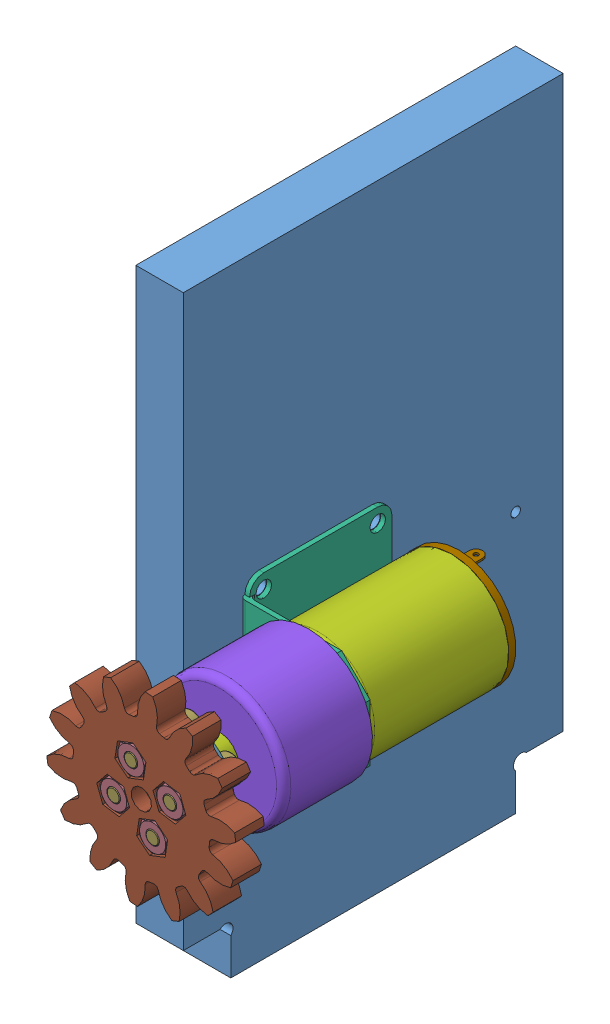
SolidWorks assembly moteur-complet, configuration Défaut. Lengths in mm.
Overall size (63.55 130 103.25).
26 component instances, 15 part files, 14 mates.
Components (placement in the parent):
- moteur-platine-1: moteur-platine [Défaut] at (-59.9962 -68.9698 170) size (10 130 80)
- Grove button-1: Grove button [Défaut] at (-60.7015 -11.8903 110) x (0 -1 0) z (0 0 -1) size (20 11.6 23.6)
  - PCB grove 20x20-1: PCB grove 20x20 [Défaut] at (2.0795 1.2947 0) size (20 1.6 23.6)
  - 603 resistor 102-1: 603 resistor 102 [Default] at (2.0895 2.8947 -6.319) x (0 0 1) z (-1 0 0) size (2.36 0.62 1.03)
  - tactileswitch-CMS-1: tactileswitch-CMS [Default] at (-2.4169 2.8947 0.0035) x (0 0 1) z (-1 0 0) size (8.41 4.95 6.01)
  - Connecteur Grove (droit CMS)-1: Connecteur Grove (droit CMS) [Défaut] at (5.0795 2.8947 0) x (-1 0 0) z (0 1 0) size (6.5 14 10)
  - 603 resistor 102-2: 603 resistor 102 [Default] at (3.5895 2.8947 -6.319) x (0 0 1) z (-1 0 0) size (2.36 0.62 1.03)
- moteur MFA-1: moteur MFA [Défaut] at (-37.4916 -12.5198 142.6632) x (0 0 -1) z (0 -1 0) size (69.13 27.9 30)
  - moteur-support-1: moteur-support [Défaut] at (-14.3868 -12.5047 0) size (31 26.4 30)
  - moteur-corps-1: moteur-corps [Défaut] at (14.8132 1.8953 0) x (0 0 1) z (-1 0 0) size (24 24 62.63)
  - moteur-capuchon-1: moteur-capuchon [Défaut] at (-15.3868 1.8953 0) x (0 0 1) z (-1 0 0) size (27 27 18.7)
  - moteur-arriere-1: moteur-arriere [Défaut] at (16.3132 1.8953 0) x (0 0 1) z (-1 0 0) size (24 24 6.5)
- entretoise-grove-6: entretoise-grove [Défaut] at (-61.9962 -13.9698 120) x (0 0 -1) z (1 0 0) size (4 4 2)
- entretoise-grove-7: entretoise-grove [Défaut] at (-61.9962 -13.9698 100) x (0 0 -1) z (1 0 0) size (4 4 2)
- engrenage-complet-1: engrenage-complet [Défaut] at (-35.1676 -12.7474 193.25) x (0.932852 0.36026 0) z (0 0 -1) size (39.32 40 13)
  - engrenage-1: engrenage [Défaut] at (1.0609 0.1936 0) size (39.32 40 6)
  - vis-chc-2: vis-chc [Vis CHC M3x10] at (6.0322 -0.3667 10) x (0.997256 0.074024 0) z (0.074024 -0.997256 0) size (5.5 13 5.5)
  - ecrou-h-1: ecrou-h [6012 HU M3] at (6.0322 -0.3667 0.1) x (1 0 0) z (0 1 0) size (5.5 2.4 6.35)
  - engrenage-moyeu-1: engrenage-moyeu [Défaut] at (-0.3178 -0.3667 7.5) x (0.707107 -0.707107 0) z (0 0 1) size (19 19 5)
  - vis-chc-3: vis-chc [Vis CHC M3x10] at (-0.3178 5.9833 10) x (0.997256 0.074024 0) z (0.074024 -0.997256 0) size (5.5 13 5.5)
  - vis-chc-4: vis-chc [Vis CHC M3x10] at (-6.6678 -0.3667 10) x (0.997256 0.074024 0) z (0.074024 -0.997256 0) size (5.5 13 5.5)
  - vis-chc-5: vis-chc [Vis CHC M3x10] at (-0.3178 -6.7167 10) x (0.997256 0.074024 0) z (0.074024 -0.997256 0) size (5.5 13 5.5)
  - ecrou-h-2: ecrou-h [6012 HU M3] at (-6.6678 -0.3667 0.1) x (0.5 0.866025 0) z (-0.866025 0.5 0) size (5.5 2.4 6.35)
  - ecrou-h-3: ecrou-h [6012 HU M3] at (-0.3178 5.9833 0.1) x (0.866025 0.5 0) z (-0.5 0.866025 0) size (5.5 2.4 6.35)
  - ecrou-h-4: ecrou-h [6012 HU M3] at (-0.3178 -6.7167 0.1) x (0.866025 0.5 0) z (-0.5 0.866025 0) size (5.5 2.4 6.35)
- vis-sthc-m3x5-1: vis-sthc-m3x5 [Défaut] at (-38.4304 -18.9204 185.75) x (0.517554 -0.229174 -0.824389) z (-0.404884 -0.914368 0) size (3.08 3.15 5.22)
Mates (geometry in assembly coordinates):
- Coïncidente1: coincident anti-aligned: plane of moteur-platine-1 through (-49.9962 -60.1012 161.1314) normal (1 0 0); plane of moteur MFA 12-24V-1/Support moteur-1 through (-49.9962 -24.5198 154.05) normal (-1 0 0)
- Coaxiale1: concentric anti-aligned: cylinder of moteur-platine-1 through (-59.9962 -0.5198 130.05) axis (1 0 0) radius 1.5; cylinder of moteur MFA 12-24V-1/Support moteur-1 through (-23.5962 -0.5198 130.05) axis (-1 0 0) radius 1.65
- Coaxiale2: concentric anti-aligned: cylinder of moteur-platine-1 through (-59.9962 -24.5198 130.05) axis (1 0 0) radius 1.5; cylinder of moteur MFA 12-24V-1/Support moteur-1 through (-23.5962 -24.5198 130.05) axis (-1 0 0) radius 1.65
- Coaxiale9: concentric anti-aligned: cylinder of Grove button-1/PCB grove 20x20-1 through (-63.5962 -13.9698 120) axis (1 0 0) radius 1.1; cylinder of entretoise-grove-6 through (-59.9962 -13.9698 120) axis (-1 0 0) radius 1.2
- Coaxiale10: concentric anti-aligned: cylinder of Grove button-1/PCB grove 20x20-1 through (-63.5962 -13.9698 100) axis (1 0 0) radius 1.1; cylinder of entretoise-grove-7 through (-59.9962 -13.9698 100) axis (-1 0 0) radius 1.2
- Coïncidente11: coincident anti-aligned: plane of Grove button-1/PCB grove 20x20-1 through (-61.9962 -13.9698 110) normal (1 0 0); plane of entretoise-grove-7 through (-61.9962 -13.9698 100) normal (-1 0 0)
- Coïncidente12: coincident anti-aligned: plane of Grove button-1/PCB grove 20x20-1 through (-61.9962 -13.9698 110) normal (1 0 0); plane of entretoise-grove-6 through (-61.9962 -13.9698 120) normal (-1 0 0)
- Coïncidente13: coincident anti-aligned: plane of moteur-platine-1 through (-59.9962 -60.1012 161.1314) normal (-1 0 0); plane of entretoise-grove-7 through (-59.9962 -13.9698 100) normal (1 0 0)
- Coaxiale11: concentric anti-aligned: cylinder of moteur-platine-1 through (-59.9962 -13.9698 100) axis (1 0 0) radius 1; cylinder of entretoise-grove-7 through (-59.9962 -13.9698 100) axis (-1 0 0) radius 1.2
- Coaxiale12: concentric anti-aligned: cylinder of moteur-platine-1 through (-59.9962 -13.9698 120) axis (1 0 0) radius 1; cylinder of entretoise-grove-6 through (-59.9962 -13.9698 120) axis (-1 0 0) radius 1.2
- Distance2: distance = 10.5 mm anti-aligned: plane of engrenage-complet-1/engrenage-1 through (-35.5962 -12.5198 187.25) normal (0 0 -1); plane of moteur MFA-1/moteur-capuchon-1 through (-35.5962 -12.5198 176.75) normal (0 0 1)
- Coaxiale13: concentric aligned: cylinder of engrenage-complet-1/engrenage-moyeu-1 through (-42.0744 -27.1497 185.75) axis (0.404884 0.914368 0) radius 1.5; cone of vis-sthc-m3x5-1 through (-36.5072 -14.5771 185.75) axis (0.404884 0.914368 0)
- Coaxiale14: concentric anti-aligned: cylinder of moteur MFA-1/moteur-corps-1 through (-35.5962 -12.5198 190.48) axis (0 0 -1) radius 2; cylinder of engrenage-complet-1/engrenage-moyeu-1 through (-35.5962 -12.5198 183.25) axis (0 0 1) radius 2
- Tangent1: tangent anti-aligned: cylinder of moteur MFA-1/moteur-corps-1 through (-35.5962 -12.5198 190.48) axis (0 0 -1) radius 2; plane of vis-sthc-m3x5-1 through (-36.406 -14.3485 185.75) normal (0.404884 0.914368 0)
